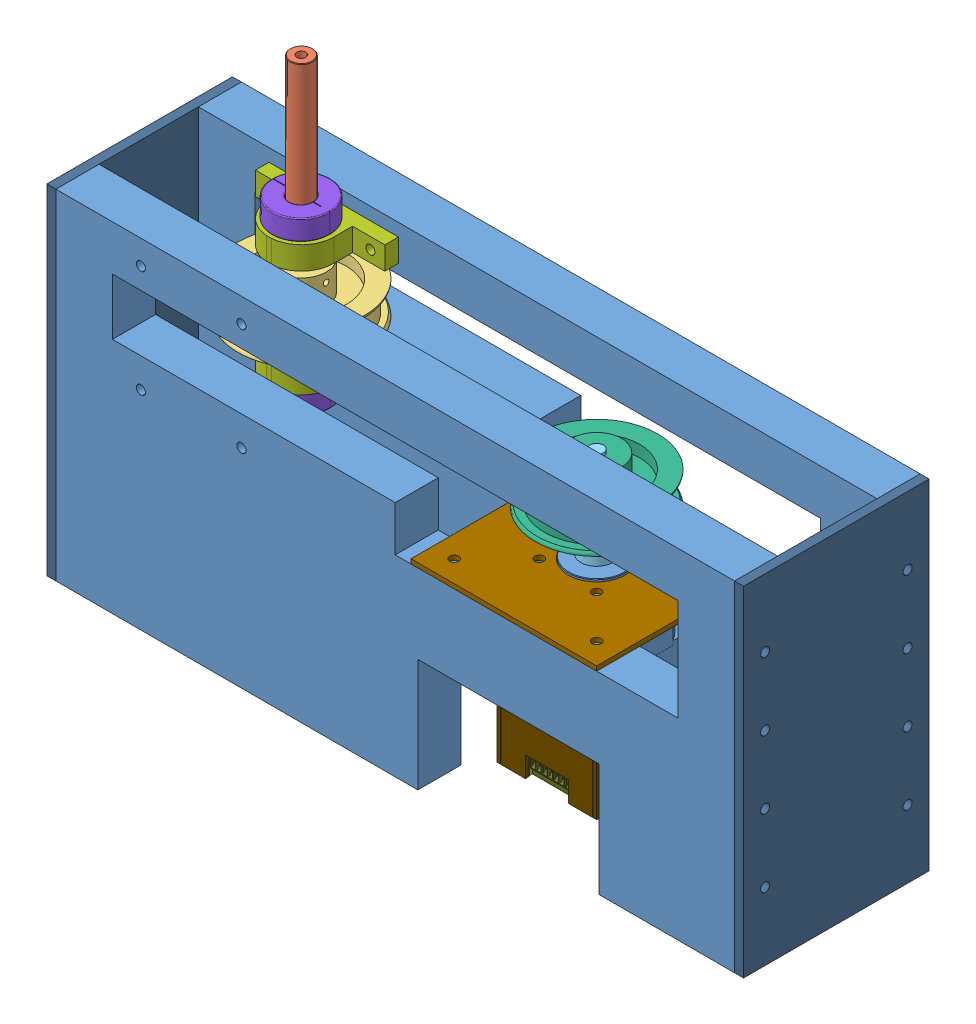
SolidWorks assembly Clock Arm, configuration Default. Lengths in mm.
Overall size (308 207 82.04).
51 component instances, 28 part files, 36 mates.
Components (placement in the parent):
- side 1-1: side 1 [Default] at (-40.4495 0.638 20.9112) size (300 150 19.05)
- shaft-1: shaft [Default] at (19.363 132.638 35.1982) x (0 -1 0) z (0 0 1) size (150 10 10)
- main pulley-1: main pulley [Default] at (19.363 114.788 35.1982) x (1 0 0) z (0 1 0) size (56 56 22.3)
- side 1-2: side 1 [Default] at (-40.4495 0.638 83.9032) size (300 150 19.05)
- BLY17MDA Series-1: BLY17MDA Series [Default] at (177.8996 9.7174 63.2022) x (-1 0 0) z (0 -1 0) size (48.3 43.99 99.92)
  - 12Pan Cross Head_AI_CR-PHMS 0.112-40x0.5x0.5-S-1: 12Pan Cross Head_AI_CR-PHMS 0.112-40x0.5x0.5-S [Default] at (3.175 3.175 2.032) x (0 0 -1) z (1 0 0) size (14.86 5.56 5.64)
  - Standoff, 4-40x.187_4-40 X .750-1: Standoff, 4-40x.187_4-40 X .750 [Default] at (3.175 37.465 -10.2235) size (5.5 4.76 19.05)
  - 12Pan Cross Head_AI_CR-PHMS 0.112-40x0.25x0.25-S-1: 12Pan Cross Head_AI_CR-PHMS 0.112-40x0.25x0.25-S [Default] at (-3.7084 10.795 -3.175) size (8.51 5.56 5.64)
  - Heat Sink, BLY17MDA Series-1: Heat Sink, BLY17MDA Series [Default] at origin size (40.64 40.64 6.53)
  - Machine Screw Nut Hex_AI_MSHXNUT 0.099-56-D-S-1: Machine Screw Nut Hex_AI_MSHXNUT 0.099-56-D-S [Default] at (3.175 3.175 -11.8999) x (0.861062 0.5085 0) z (0 0 -1) size (4.78 5.51 1.68)
  - AA5395-1PCB-1: AA5395-1PCB [Default] at (40.005 0.635 -10.2235) x (-1 0 0) z (0 0 -1) size (39.37 40.24 28.36)
    - LED-T-1-Series_LED-T-1-GRN-1: LED-T-1-Series_LED-T-1-GRN [Default] at (20.955 36.195 -6.1595) x (1 0 0) z (0 1 0) size (4.06 12.37 3.61)
    - CON-B5B-EH-A-1: CON-B5B-EH-A [Default] at (23.2024 12.0142 0) x (1 0 0) z (0 -1 0) size (15.24 9.17 3.81)
    - LED-LTM Series_LED-LTM180-1: LED-LTM Series_LED-LTM180 [Default] at (20.955 36.195 -2.2225) x (0 1 0) z (-1 0 0) size (5.16 4.57 5.16)
    - TRS-IRFU3607PBF with 90degree bent UP legs-1: TRS-IRFU3607PBF with 90degree bent UP legs [Default] at (14.605 12.1748 -3.8735) x (-1 0 0) z (0 1 0) size (9.78 4.95 6.53)
    - TRS-IRFU3607PBF with 90degree bent UP legs-2: TRS-IRFU3607PBF with 90degree bent UP legs [Default] at (24.765 5.656 -3.8735) x (1 0 0) z (0 -1 0) size (9.78 4.95 6.53)
    - AA5395PCB-1: AA5395PCB [Default] at origin size (39.37 39.37 1.59)
    - TRS-IRFU3607PBF with 90degree bent UP legs-3: TRS-IRFU3607PBF with 90degree bent UP legs [Default] at (14.605 33.7648 -3.8735) x (-1 0 0) z (0 1 0) size (9.78 4.95 6.53)
    - TRS-IRFU3607PBF with 90degree bent UP legs-4: TRS-IRFU3607PBF with 90degree bent UP legs [Default] at (24.765 16.451 -3.8735) x (1 0 0) z (0 -1 0) size (9.78 4.95 6.53)
    - TRS-IRFU3607PBF with 90degree bent UP legs-5: TRS-IRFU3607PBF with 90degree bent UP legs [Default] at (24.765 27.246 -3.8735) x (1 0 0) z (0 -1 0) size (9.78 4.95 6.53)
    - TRS-IRFU3607PBF with 90degree bent UP legs-6: TRS-IRFU3607PBF with 90degree bent UP legs [Default] at (14.605 22.9698 -3.8735) x (-1 0 0) z (0 1 0) size (9.78 4.95 6.53)
    - ESW-106-33-T-S_LEAD STYLE33LOCKING LEADSNonePINS6PLATINGTPOLARIZENoneROWS-1: ESW-106-33-T-S_LEAD STYLE33LOCKING LEADSNonePINS6PLATINGTPOLARIZENoneROWS [Default] at (36.8301 25.4 7.62) x (1 0 0) z (0 -1 0) size (2.54 18.42 15.75)
    - RES-3W-JAPSTYLE-1: RES-3W-JAPSTYLE [Default] at (26.3652 36.3474 12.7) x (0 0 1) z (-0.000937 -1 0) size (20.34 8.01 5.08)
    - 1725708-1: 1725708 [Default] at (24.765 23.458 4.8639) x (0 1 0) z (-1 0 0) size (6.2 12 18.24)
    - CAP-0223-1: CAP-0223 [Default] at (10.4902 34.29 0) x (-1 0 0) z (0 1 0) size (10.16 20.32 10.16)
  - 12Pan Cross Head_AI_CR-PHMS 0.112-40x0.25x0.25-S-2: 12Pan Cross Head_AI_CR-PHMS 0.112-40x0.25x0.25-S [Default] at (-3.7084 29.845 -3.175) size (8.51 5.56 5.64)
  - Cover, BLY17MDA Series-1: Cover, BLY17MDA Series [Default] at (42.3164 42.3164 -34.925) x (0 -1 0) z (1 0 0) size (43.99 34.92 43.99)
  - Standoff, 4-40x.187_4-40 X .750-2: Standoff, 4-40x.187_4-40 X .750 [Default] at (37.465 37.465 -10.2235) size (5.5 4.76 19.05)
  - 12Pan Cross Head_AI_CR-PHMS 0.112-40x0.25x0.25-S-3: 12Pan Cross Head_AI_CR-PHMS 0.112-40x0.25x0.25-S [Default] at (44.3484 10.795 -3.175) x (-1 0 0) z (0 0.999909 0.013526) size (8.51 5.56 5.64)
  - Machine Screw Nut Hex_AI_MSHXNUT 0.099-56-D-S-2: Machine Screw Nut Hex_AI_MSHXNUT 0.099-56-D-S [Default] at (37.465 3.175 -11.8999) x (0.87114 0.491034 0) z (0 0 -1) size (4.78 5.51 1.68)
  - 12Pan Cross Head_AI_CR-PHMS 0.112-40x0.25x0.25-S-4: 12Pan Cross Head_AI_CR-PHMS 0.112-40x0.25x0.25-S [Default] at (3.175 37.465 -32.893) x (0 0 1) z (-1 0 0) size (8.51 5.56 5.64)
  - BLY171S-24V-4000-02_BLY171S-1: BLY171S-24V-4000-02_BLY171S [Default] at (20.32 20.32 -75.9206) x (0 -1 0) z (0 0 -1) size (42.01 42.01 90.14)
  - AA5396-1PCB-1: AA5396-1PCB [Default] at (40.005 17.78 -30.861) x (-1 0 0) z (0 0 -1) size (39.37 22.23 11.43)
    - CON-0075-1: CON-0075 [Default] at (38.1 15.875 -1.5875) x (0 -1 0) z (0 0 -1) size (15.24 2.54 11.43)
    - AA5396PCB-1: AA5396PCB [Default] at origin size (39.37 22.23 1.59)
  - 12Pan Cross Head_AI_CR-PHMS 0.112-40x0.5x0.5-S-2: 12Pan Cross Head_AI_CR-PHMS 0.112-40x0.5x0.5-S [Default] at (37.465 3.175 2.032) x (0 0 -1) z (1 0 0) size (14.86 5.56 5.64)
  - 12Pan Cross Head_AI_CR-PHMS 0.112-40x0.5x0.5-S-3: 12Pan Cross Head_AI_CR-PHMS 0.112-40x0.5x0.5-S [Default] at (3.175 37.465 2.032) x (0 0 -1) z (1 0 0) size (14.86 5.56 5.64)
  - Pan Cross Head_AI_CR-PHMS 0.112-40x0.188x0.188-S-1: Pan Cross Head_AI_CR-PHMS 0.112-40x0.188x0.188-S [Default] at (20.32 33.02 -31.369) x (0 0 -1) z (1 0 0) size (6.93 5.56 5.64)
  - 12Pan Cross Head_AI_CR-PHMS 0.112-40x0.25x0.25-S-5: 12Pan Cross Head_AI_CR-PHMS 0.112-40x0.25x0.25-S [Default] at (37.465 37.465 -32.893) x (0 0 1) z (-1 0 0) size (8.51 5.56 5.64)
  - 12Pan Cross Head_AI_CR-PHMS 0.112-40x0.5x0.5-S-4: 12Pan Cross Head_AI_CR-PHMS 0.112-40x0.5x0.5-S [Default] at (37.465 37.465 2.032) x (0 0 -1) z (1 0 0) size (14.86 5.56 5.64)
  - Pan Cross Head_AI_CR-PHMS 0.112-40x0.188x0.188-S-2: Pan Cross Head_AI_CR-PHMS 0.112-40x0.188x0.188-S [Default] at (20.32 7.62 -31.369) x (0 0 -1) z (1 0 0) size (6.93 5.56 5.64)
  - 12Pan Cross Head_AI_CR-PHMS 0.112-40x0.25x0.25-S-6: 12Pan Cross Head_AI_CR-PHMS 0.112-40x0.25x0.25-S [Default] at (44.3484 29.845 -3.175) x (-1 0 0) z (0 0.999976 0.006953) size (8.51 5.56 5.64)
- motor shaft coupling-2: motor shaft coupling [Default] at (157.5796 104.686 42.8822) x (-0.837169 0 -0.546944) z (0 1 0) size (14 14 40)
- drive pulley-1: drive pulley [Default] at (157.5796 114.788 42.8822) x (1 0 0) z (0 1 0) size (54 54 20.6)
- bearing-1: bearing [Default] at (47.963 87.538 20.9112) x (-1 0 0) z (0 1 0) size (57.2 28.6 10.1)
- bearing-2: bearing [Default] at (47.963 134.938 20.9112) x (-1 0 0) z (0 1 0) size (57.2 28.6 10.1)
- collar-1: collar [57445K25] at (19.363 149.538 35.3252) x (1 0 0) z (0 -1 0) size (25.4 25.65 9)
- collar-2: collar [57445K25] at (19.363 83.038 35.0712) x (1 0 0) z (0 1 0) size (25.4 25.65 9)
- motor plate-1: motor plate [Default] at (198.6006 87.638 83.9032) x (-1 0 0) z (0 0 1) size (82.04 2 82.04)
- Side Plate-1: Side Plate [Default] at (259.5505 0.638 20.9112) x (0 0 -1) z (1 0 0) size (82.04 150 4)
- Side Plate-2: Side Plate [Default] at (-44.4495 0.638 20.9112) x (0 0 -1) z (1 0 0) size (82.04 150 4)
Mates (geometry in assembly coordinates):
- Parallel1: parallel: plane of side 1-1 through (-40.4495 150.638 1.8612) normal (0 1 0); plane of shaft-1 through (19.363 57.638 35.1982) normal (0 -1 0)
- Concentric1: concentric: cylinder of shaft-1 through (19.363 207.638 35.1982) axis (0 -1 0) radius 5; cylinder of main pulley-1 through (19.363 106.923 35.1982) axis (0 1 0) radius 5.0063
- Distance1: distance = 2 mm: plane of main pulley-1 through (19.363 107.638 35.1982) normal (0 -1 0); plane of side 1-1 through (-15.4495 105.638 -249.3857) normal (0 1 0)
- Coincident11: coincident: plane of side 1-1 through (-40.4495 0.638 1.8612) normal (-1 0 0); plane of side 1-2 through (-40.4495 0.638 64.8532) normal (-1 0 0)
- Coincident12: coincident: plane of side 1-1 through (-40.4495 150.638 1.8612) normal (0 1 0); plane of side 1-2 through (-40.4495 150.638 64.8532) normal (0 1 0)
- Parallel3: parallel: plane of side 1-2 through (-15.4495 105.638 -186.3937) normal (0 1 0); plane of BLY17MDA Series-1/BLY171S-24V-4000-02_BLY171S-1 through (157.5796 85.638 42.8822) normal (0 1 0)
- Concentric9: concentric: cylinder of BLY17MDA Series-1/BLY171S-24V-4000-02_BLY171S-1 through (157.5796 107.482 42.8822) axis (0 -1 0) radius 2.5006; cylinder of motor shaft coupling-2 through (157.5796 105.436 42.8822) axis (0 -1 0) radius 2.5
- Distance7: distance = 1 mm: plane of BLY17MDA Series-1/BLY171S-24V-4000-02_BLY171S-1 through (157.5796 88.686 42.8822) normal (0 1 0); plane of motor shaft coupling-2 through (157.5796 89.686 42.8822) normal (0 -1 0)
- Distance9: distance = 10 mm: plane of side 1-1 through (-15.4495 130.638 -249.3857) normal (1 0 0); cylinder of main pulley-1 through (19.363 106.923 35.1982) axis (0 1 0) radius 24.8125
- Coincident26: coincident: plane of side 1-1 through (234.5505 85.638 1.8612) normal (0 1 0); plane of BLY17MDA Series-1/BLY171S-24V-4000-02_BLY171S-1 through (157.5796 85.638 42.8822) normal (0 1 0)
- Distance10: distance = 50 mm: plane of shaft-1 through (19.363 57.638 35.1982) normal (0 -1 0); plane of main pulley-1 through (19.363 107.638 35.1982) normal (0 -1 0)
- Concentric11: concentric: cylinder of motor shaft coupling-2 through (157.5796 130.936 42.8822) axis (0 -1 0) radius 3; cylinder of drive pulley-1 through (157.5796 106.923 42.8822) axis (0 1 0) radius 3.0062
- Coincident29: coincident: plane of main pulley-1 through (19.363 121.938 35.1982) normal (0 1 0); plane of drive pulley-1 through (157.5796 121.938 42.8822) normal (0 1 0)
- Concentric12: concentric: cylinder of shaft-1 through (19.363 207.638 35.1982) axis (0 -1 0) radius 5; cylinder of bearing-1 through (19.363 87.538 35.1982) axis (0 1 0) radius 5
- Coincident32: coincident: plane of side 1-1 through (-40.4495 150.638 20.9112) normal (0 0 1); plane of bearing-1 through (47.963 97.638 20.9112) normal (0 0 -1)
- Distance12: distance = 10 mm: plane of bearing-1 through (47.963 97.638 49.5112) normal (0 1 0); plane of main pulley-1 through (19.363 107.638 35.1982) normal (0 -1 0)
- Concentric13: concentric: cylinder of shaft-1 through (19.363 207.638 35.1982) axis (0 -1 0) radius 5; cylinder of bearing-2 through (19.363 134.938 35.1982) axis (0 1 0) radius 5
- Coincident34: coincident: plane of side 1-1 through (-40.4495 150.638 20.9112) normal (0 0 1); plane of bearing-2 through (47.963 145.038 20.9112) normal (0 0 -1)
- Distance13: distance = 5 mm: plane of bearing-2 through (47.963 134.938 49.5112) normal (0 -1 0); plane of main pulley-1 through (19.363 129.938 35.1982) normal (0 1 0)
- Concentric14: concentric: cylinder of shaft-1 through (19.363 207.638 35.1982) axis (0 -1 0) radius 5; cylinder of collar-1 through (19.363 145.038 35.1982) axis (0 1 0) radius 5
- Coincident37: coincident: plane of bearing-2 through (47.963 145.038 49.5112) normal (0 1 0); plane of collar-1 through (19.363 145.038 35.4522) normal (0 -1 0)
- Coincident38: coincident: plane of bearing-1 through (47.963 87.538 49.5112) normal (0 -1 0); plane of collar-2 through (19.363 87.538 34.9442) normal (0 1 0)
- Concentric15: concentric: cylinder of shaft-1 through (19.363 207.638 35.1982) axis (0 -1 0) radius 5; cylinder of collar-2 through (19.363 87.538 35.1982) axis (0 -1 0) radius 5
- Distance15: distance = 130.43 mm: cylinder of shaft-1 through (19.363 207.638 35.1982) axis (0 -1 0) radius 5; cylinder of motor shaft coupling-2 through (157.5796 130.936 42.8822) axis (0 -1 0) radius 3
- Coincident40: coincident: plane of BLY17MDA Series-1/BLY171S-24V-4000-02_BLY171S-1 through (157.5796 85.638 42.8822) normal (0 1 0); plane of motor plate-1 through (198.6006 85.638 1.8612) normal (0 -1 0)
- Concentric20: concentric: cylinder of BLY17MDA Series-1/BLY171S-24V-4000-02_BLY171S-1 through (157.5796 88.686 42.8822) axis (0 -1 0) radius 12.5476; cylinder of motor plate-1 through (157.5796 87.638 42.8822) axis (0 -1 0) radius 12.5476
- Coincident44: coincident: plane of side 1-1 through (-40.4495 150.638 1.8612) normal (0 0 -1); plane of motor plate-1 through (198.6006 85.638 1.8612) normal (0 0 -1)
- Coincident45: coincident: plane of side 1-2 through (-40.4495 150.638 83.9032) normal (0 0 1); plane of motor plate-1 through (198.6006 85.638 83.9032) normal (0 0 1)
- Parallel4: parallel: cylinder of BLY17MDA Series-1/BLY171S-24V-4000-02_BLY171S-1 through (170.3046 85.638 30.1572) axis (0 1 0) radius 1.65; cylinder of motor plate-1 through (170.2796 87.638 30.1822) axis (0 -1 0) radius 2
- InPlace1: in place: plane of side 1-1 through (259.5505 0.638 1.8612) normal (1 0 0); plane of ? through (259.5505 0 0) normal (1 0 0); moOrthogonalPlaneRef_w of side 1-1 through (259.5505 0.638 1.8612) normal (1 0 0); line of ? through (-55 259.5505 0) axis (0 0 1); plane of side 1-1 through (259.5505 0.638 1.8612) normal (1 0 0); plane of ? through (259.5505 0 0) normal (0 0 -1); plane of side 1-1 through (259.5505 0.638 1.8612) normal (1 0 0); unknown of Side Plate-1
- Coincident46: coincident: plane of side 1-1; plane of Side Plate-1
- Coincident47: coincident: moOrthogonalPlaneRef_w of side 1-1 through (259.5505 0.638 20.9112) normal (0 1 0); plane of Side Plate-1
- Coincident48: coincident: moOrthogonalPlaneRef_w of side 1-1 through (259.5505 0.638 20.9112) normal (0 0 1); plane of Side Plate-1 through (259.5505 0.638 20.9112) normal (0 0 -1)
- Coincident49: coincident: plane of side 1-1 through (-40.4495 0.638 1.8612) normal (-1 0 0); plane of Side Plate-2 through (-40.4495 0.638 1.8612) normal (1 0 0)
- Coincident50: coincident: plane of side 1-1 through (-40.4495 150.638 1.8612) normal (0 1 0); plane of Side Plate-2 through (-40.4495 150.638 1.8612) normal (0 1 0)
- Coincident51: coincident: plane of side 1-2 through (-40.4495 150.638 83.9032) normal (0 0 1); plane of Side Plate-2 through (-40.4495 150.638 83.9032) normal (0 0 1)
